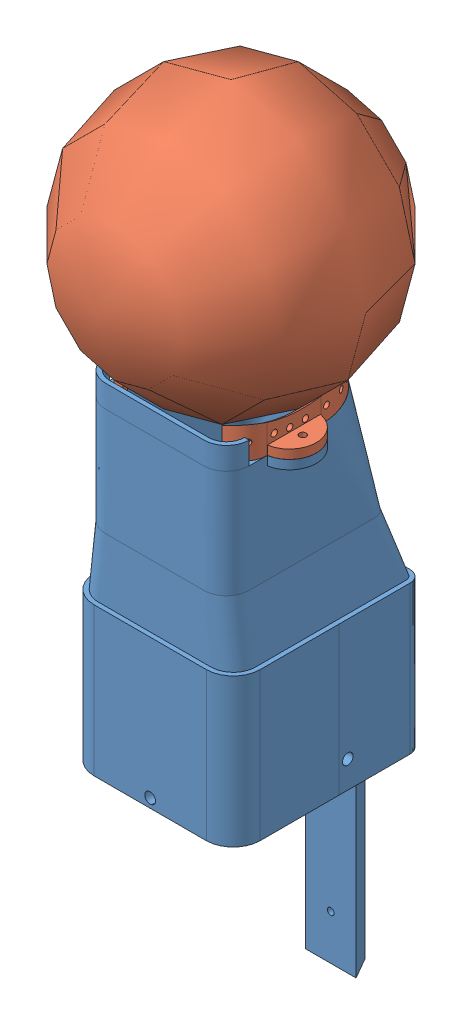
SolidWorks assembly npx_hstage_longear_withbase, configuration Default. Lengths in mm.
Overall size (40.64 68.04 35.8).
2 component instances, 2 part files, 3 mates.
Components (placement in the parent):
- npx_cap_tall_longrear-1: npx_cap_tall_longrear [Default] at (-17.0104 29.1167 11.2818) size (40.64 68.04 35.8)
- npx_cap_base-1: npx_cap_base [Default] at (-17.0104 29.1167 11.2818) x (-1 0 0) z (0 0 1) size (30 30.25 30)
Mates (geometry in assembly coordinates):
- Coincident1: coincident anti-aligned: plane of npx_cap_tall_longrear_wire_holder_with_lateral_cut-1 through (-16.5104 29.1167 10.7818) normal (0 1 0); plane of npx_cap_base-1 through (-17.5104 29.1167 10.7818) normal (0 -1 0)
- Concentric1: concentric anti-aligned: circle of npx_cap_tall_longrear_wire_holder_with_lateral_cut-1; circle of npx_cap_base-1
- Concentric2: concentric anti-aligned: cylinder of npx_cap_tall_longrear_wire_holder_with_lateral_cut-1; cylinder of npx_cap_base-1 through (-26.0104 29.1167 13.7818) axis (0 -1 0) radius 0.375
